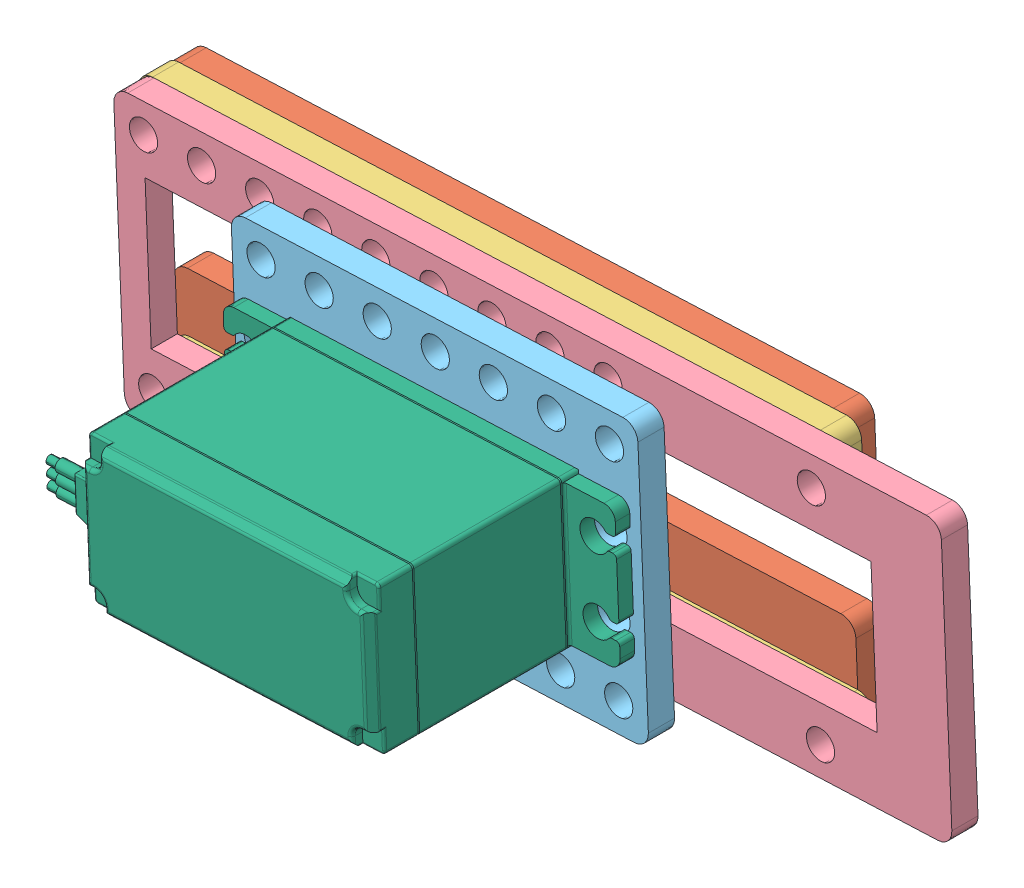
SolidWorks assembly Assem3, configuration Default. Lengths in mm.
Overall size (115.7 42.77 47.6).
8 component instances, 6 part files, 19 mates.
Components (placement in the parent):
- ATTACH LINEAR-1: ATTACH LINEAR [Default] at (74.3516 -7.7141 118.495) x (0.999532 0.030588 0) z (0 0 1) size (18 18 7.5)
- SUPPORTSERVO1-1: SUPPORTSERVO1 [Default] at (126.0036 13.4832 118.495) x (-0.99911 -0.042175 0) z (0.042175 -0.99911 0) size (94 3.6 14)
- SUPPORTSERVO2-1: SUPPORTSERVO2 [Default] at (127.8025 13.5592 122.095) x (-0.99911 -0.042175 0) z (0.042175 -0.99911 0) size (96 3.6 6)
- SUPPORTSERVO3-1: SUPPORTSERVO3 [Default] at (145.9858 14.3267 125.695) x (-0.99911 -0.042175 0) z (0.042175 -0.99911 0) size (114 3.6 38)
- SUPPORTSERVO4-1: SUPPORTSERVO4 [Default] at (35.6881 -28.3631 133.495) x (0.99911 0.042175 0) z (-0.042175 0.99911 0) size (56 3.6 38)
- MG995.step-1: MG995.step [Default] at (84.3427 -7.2923 162.495) x (-0.99911 -0.042175 0) z (0 0 -1) size (55.5 20 44.5)
- SUPPORTSERVO2-2: SUPPORTSERVO2 [Default] at (129.6045 -24.3986 118.495) x (-0.99911 -0.042175 0) z (-0.042175 0.99911 0) size (96 3.6 6)
- SUPPORTSERVO1-2: SUPPORTSERVO1 [Default] at (127.6062 -24.483 114.895) x (-0.99911 -0.042175 0) z (-0.042175 0.99911 0) size (94 3.6 14)
Mates (geometry in assembly coordinates):
- Concentric1: concentric anti-aligned: cylinder of ATTACH LINEAR-1 through (74.3516 -7.7141 122.995) axis (0 0 -1) radius 1.5; cylinder of MG995.step-1 through (74.3516 -7.7141 122.995) axis (0 0 1) radius 2
- Coincident1: coincident anti-aligned: plane of ATTACH LINEAR-1 through (74.3516 -7.7141 122.995) normal (0 0 1); plane of MG995.step-1 through (74.3516 -7.7141 122.995) normal (0 0 -1)
- Concentric2: concentric anti-aligned: cylinder of SUPPORTSERVO4-1 through (60.575 -13.3001 139.895) axis (0 0 -1) radius 2.25; cylinder of MG995.step-1 through (60.575 -13.3001 133.495) axis (0 0 1) radius 2
- Coincident3: coincident anti-aligned: plane of SUPPORTSERVO4-1 through (132.0826 11.738 133.495) normal (0 0 1); plane of MG995.step-1 through (84.3427 -7.2923 133.495) normal (0 0 -1)
- Coincident4: coincident anti-aligned: plane of SUPPORTSERVO4-1 through (65.0321 -18.1164 133.495) normal (-0.042175 0.99911 0); plane of MG995.step-1 through (104.7467 -16.4399 126.495) normal (0.042175 -0.99911 0)
- Coincident15: coincident aligned: plane of SUPPORTSERVO3-1 through (145.5902 -23.7238 122.095) normal (0.042175 -0.99911 0); plane of SUPPORTSERVO2-2 through (127.6062 -24.483 122.095) normal (0.042175 -0.99911 0)
- Coincident20: coincident anti-aligned: plane of SUPPORTSERVO2-1 through (34.0549 5.5983 122.095) normal (0 0 1); plane of SUPPORTSERVO3-1 through (35.6037 -26.3648 122.095) normal (0 0 -1)
- Coincident21: coincident aligned: plane of SUPPORTSERVO2-1 through (125.8043 13.4748 118.495) normal (-0.042175 0.99911 0); plane of SUPPORTSERVO3-1 through (143.9876 14.2424 122.095) normal (-0.042175 0.99911 0)
- Coincident23: coincident aligned: plane of SUPPORTSERVO3-1 through (143.9876 14.2424 122.095) normal (-0.042175 0.99911 0); plane of SUPPORTSERVO4-1 through (36.0837 9.6875 129.895) normal (-0.042175 0.99911 0)
- Coincident24: coincident aligned: plane of SUPPORTSERVO1-1 through (124.0054 13.3989 114.895) normal (-0.042175 0.99911 0); plane of SUPPORTSERVO2-1 through (125.8043 13.4748 118.495) normal (-0.042175 0.99911 0)
- Coincident26: coincident anti-aligned: plane of SUPPORTSERVO2-2 through (35.5194 -24.3666 118.495) normal (0 0 -1); plane of SUPPORTSERVO1-2 through (35.182 -16.3737 118.495) normal (0 0 1)
- Coincident27: coincident aligned: plane of SUPPORTSERVO3-1 through (145.5902 -23.7238 122.095) normal (0.042175 -0.99911 0); plane of SUPPORTSERVO1-2 through (125.608 -24.5673 118.495) normal (0.042175 -0.99911 0)
- Concentric4: concentric aligned: cylinder of SUPPORTSERVO3-1 through (60.231 6.7032 125.695) axis (0 0 -1) radius 1.95; cylinder of SUPPORTSERVO4-1 through (60.231 6.7032 133.495) axis (0 0 -1) radius 1.95
- Concentric6: concentric aligned: cylinder of SUPPORTSERVO1-1 through (60.231 6.7032 118.495) axis (0 0 -1) radius 1.95; cylinder of SUPPORTSERVO4-1 through (60.231 6.7032 133.495) axis (0 0 -1) radius 1.95
- Coincident28: coincident anti-aligned: plane of SUPPORTSERVO1-1 through (34.5916 -2.3862 118.495) normal (0 0 1); plane of SUPPORTSERVO2-1 through (34.0549 5.5983 118.495) normal (0 0 -1)
- Coincident29: coincident anti-aligned: plane of SUPPORTSERVO3-1 through (35.6037 -26.3648 122.095) normal (0 0 -1); plane of SUPPORTSERVO2-2 through (35.5194 -24.3666 122.095) normal (0 0 1)
- Coincident30: coincident aligned: plane of ATTACH LINEAR-1 through (74.3516 -7.7141 118.495) normal (0 0 -1); plane of SUPPORTSERVO2-2 through (35.5194 -24.3666 118.495) normal (0 0 -1)
- Concentric10: concentric anti-aligned: cylinder of SUPPORTSERVO3-1 through (37.5176 -24.2823 125.695) axis (0 0 -1) radius 1.95; cylinder of SUPPORTSERVO2-2 through (37.5176 -24.2823 118.495) axis (0 0 1) radius 1.95
- Concentric11: concentric aligned: cylinder of SUPPORTSERVO2-2 through (37.5176 -24.2823 118.495) axis (0 0 1) radius 1.95; cylinder of SUPPORTSERVO1-2 through (37.5176 -24.2823 114.895) axis (0 0 1) radius 1.95
